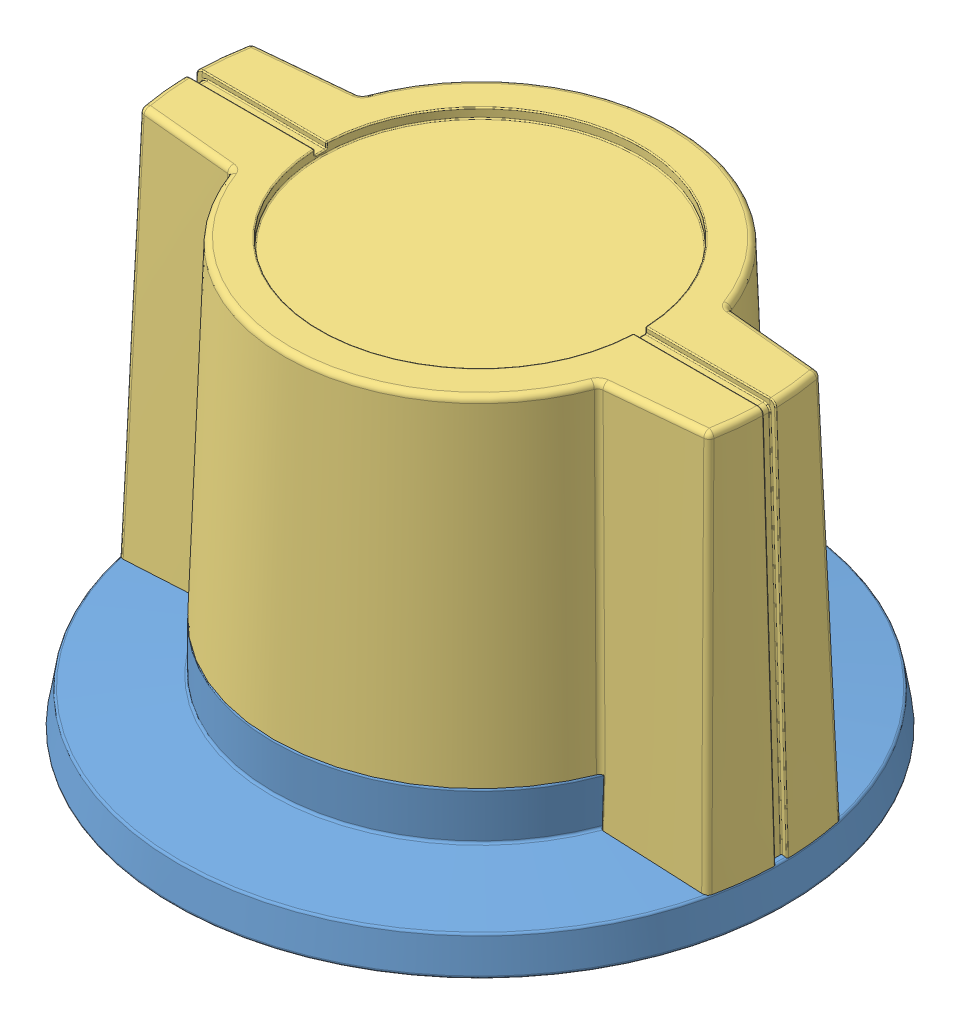
SolidWorks assembly Marconi Neve Knob 26x18, configuration Default. Lengths in mm.
Overall size (25.96 18 25.96).
4 component instances, 3 part files, 0 mates.
Components (placement in the parent):
- Marconi Neve Knob 26x18.stp-1: Marconi Neve Knob 26x18.stp [Default] at origin size (25.96 18 25.96)
  - Base_Ring_T1.stp-1: Base_Ring_T1.stp [Default] at (-1.5667 5.2372 0) size (25.96 3.99 25.96)
  - Inner_Ring_T1a.stp-1: Inner_Ring_T1a.stp [Default] at (-1.5667 5.2372 0) x (-1 0 0) z (0 1 0) size (14 14 15.25)
  - Knob_Cover_T1.stp-1: Knob_Cover_T1.stp [Default] at (-1.5667 5.2372 0) size (25.56 16.72 17.5)
